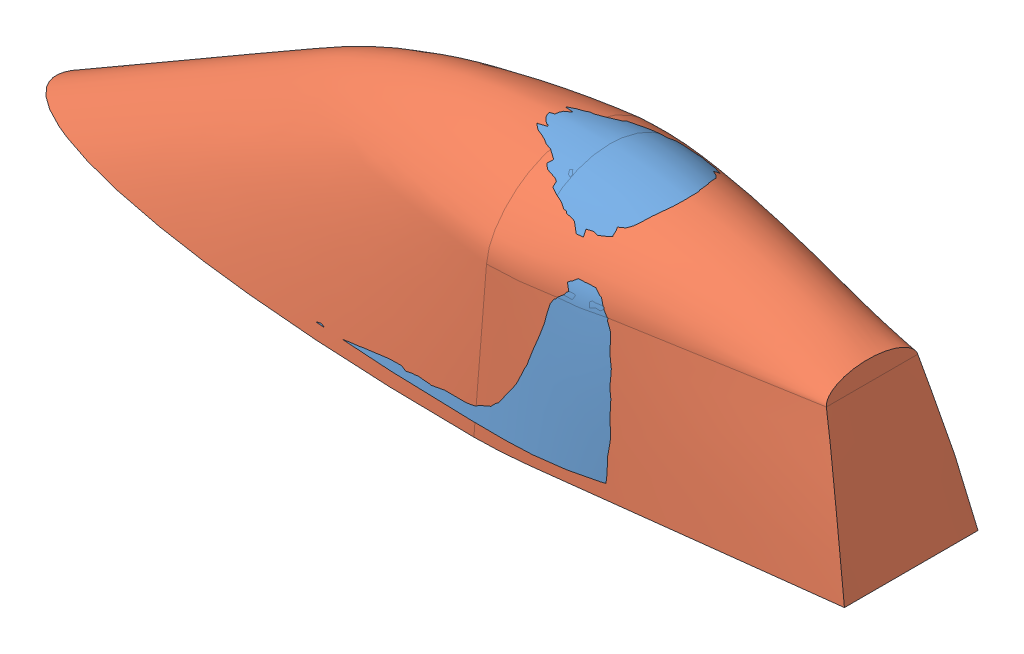
SolidWorks assembly Assem1, configuration Default. Lengths in mm.
Overall size (1688.13 425.83 575.69).
2 component instances, 2 part files, 3 mates.
Components (placement in the parent):
- windshileld4-1: windshileld4 [Default] at (819.3218 643.9788 0) size (1688.13 400.44 575.69)
- windshileld4-1-1: windshileld4-1 [Default] at (757.86 618.5788 0) size (1663.73 419.26 406.43)
Mates (geometry in assembly coordinates):
- Distance1: distance = 25.4 mm aligned: plane of windshileld4-1 through (819.3218 643.9788 0) normal (0 1 0); plane of windshileld4-1-1 through (757.86 618.5788 0) normal (0 1 0)
- Coincident3: coincident aligned: plane of windshileld4-1 through (819.3218 643.9788 0) normal (0 0 1)
- Coincident4: coincident aligned: plane of windshileld4-1-1 through (757.86 618.5788 0) normal (0 0 1)
